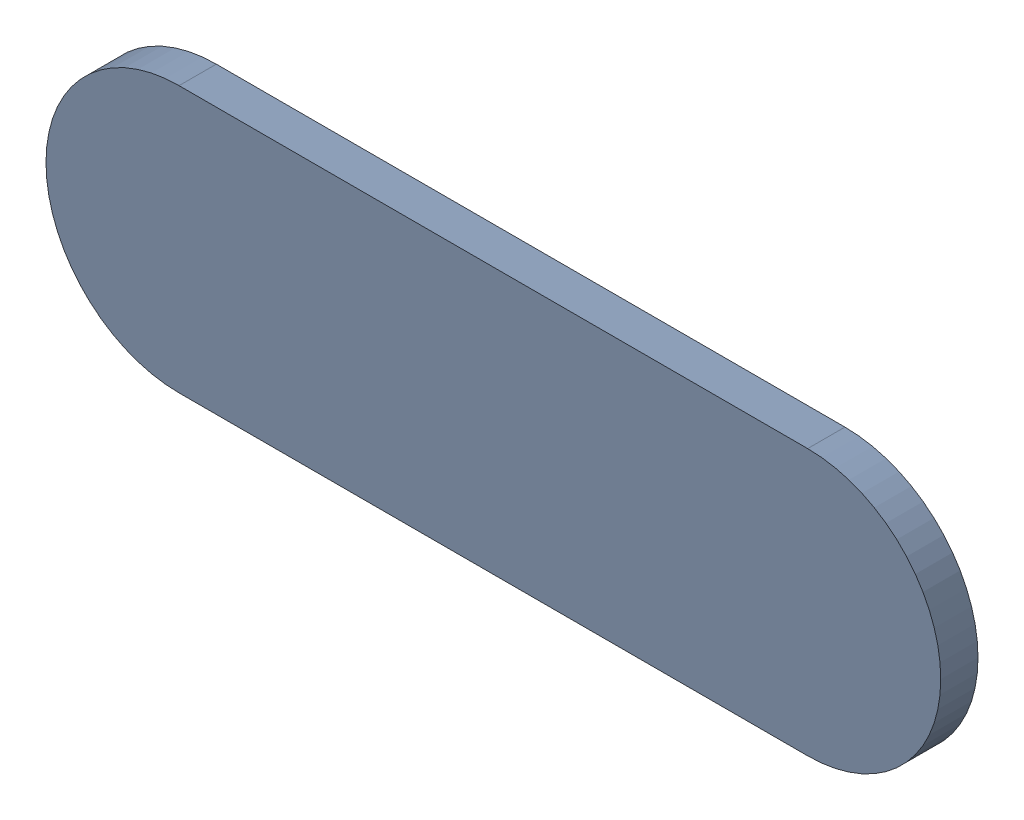
SolidWorks assembly Track (28.6mm,13.75mm)(29.2mm,13.75mm) on Top Layer, configuration Predeterminado. Lengths in mm.
Overall size (0.85 0.25 0.04).
2 component instances, 1 part files, 0 mates.
Components (placement in the parent):
- Track (28.6mm,13.75mm)(29.2mm,13.75mm) on Top Layer-1-1: Track (28.6mm,13.75mm)(29.2mm,13.75mm) on Top Layer-1 [Predeterminado] at (-68.317 -44.187 -0.0457) size (0.85 0.25 0.04)
  - Track (28.6mm,13.75mm)(29.2mm,13.75mm) on Top Layer-Part-1-1: Track (28.6mm,13.75mm)(29.2mm,13.75mm) on Top Layer-Part-1 [Predeterminado] at origin size (0.85 0.25 0.04)
